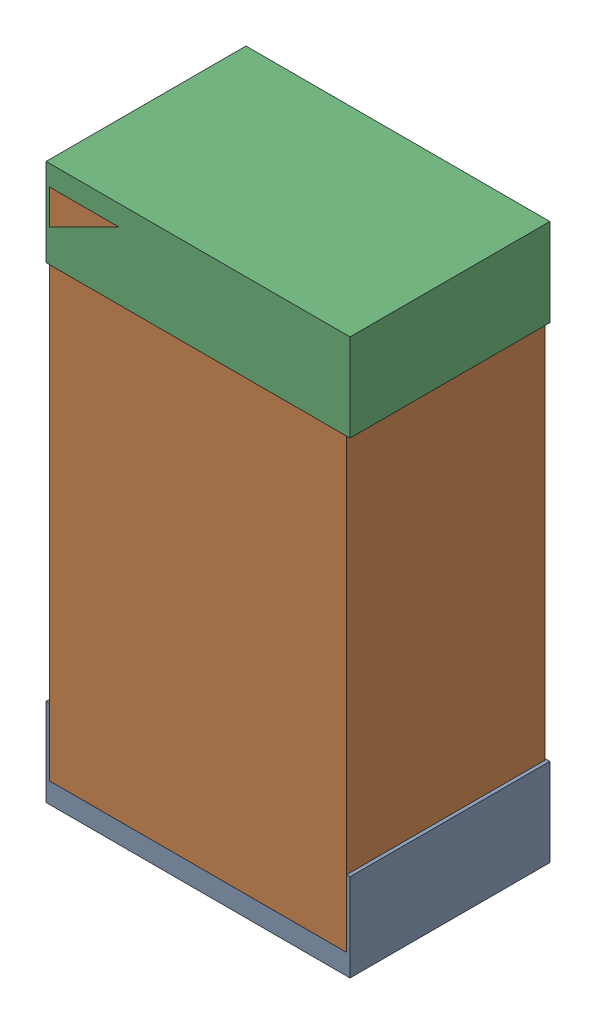
SolidWorks assembly R27Kanaloa_v2.0.0_Motor, configuration Default. Lengths in mm.
Overall size (1.3 2.38 0.85).
6 component instances, 2 part files, 0 mates.
Components (placement in the parent):
- 330415056-1: 330415056 [Default] at (84.074 92.98 -1.9574) size (1.3 0.38 0.85)
  - Extruded_2-1: Extruded_2 [Default] at origin size (1.3 0.38 0.85)
- 334787376-1: 334787376 [Default] at (84.074 93.98 -1.9524) size (1.27 2.2 0.85)
  - Extruded_16-1: Extruded_16 [Default] at origin size (1.27 2.2 0.85)
- 330415056-2: 330415056 [Default] at (84.074 94.98 -1.9574) size (1.3 0.38 0.85)
  - Extruded_2-1: Extruded_2 [Default] at origin size (1.3 0.38 0.85)
